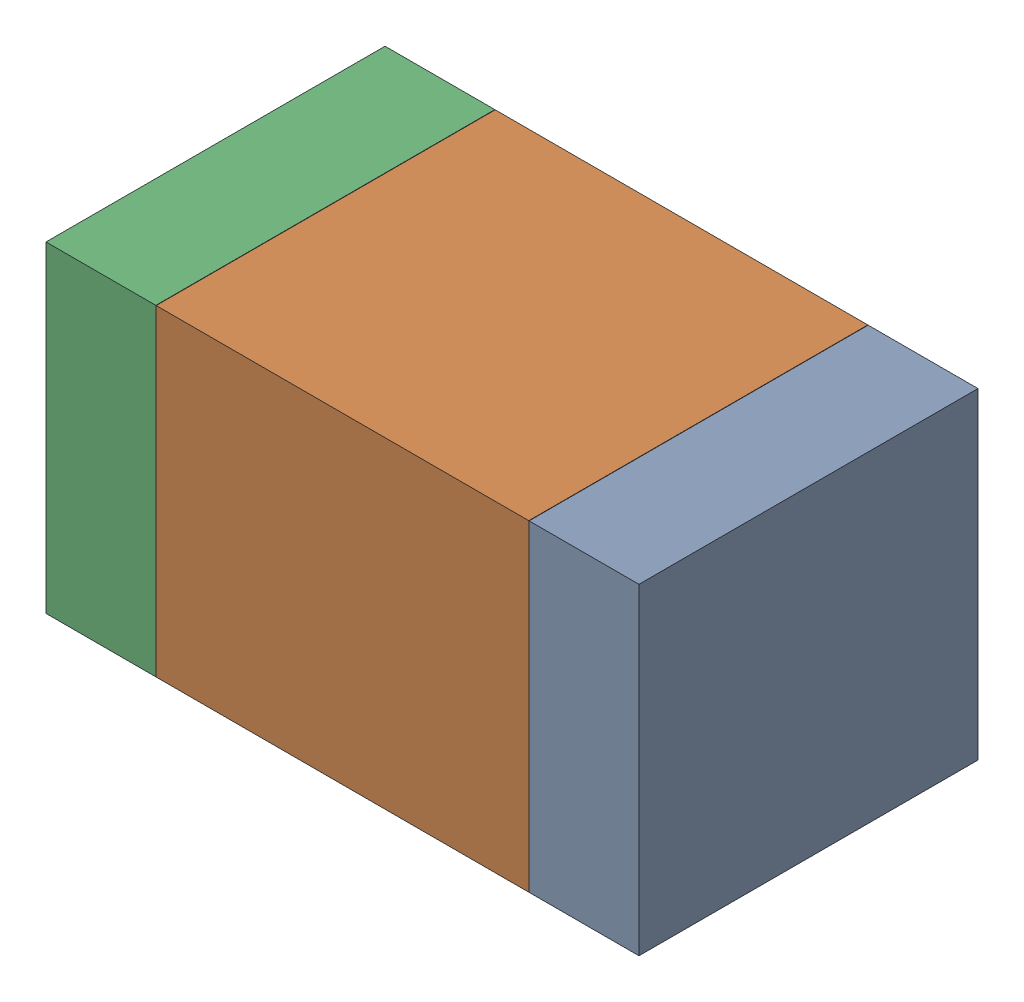
SolidWorks assembly C27, configuration Default. Lengths in mm.
Overall size (1.75 0.95 1).
6 component instances, 2 part files, 0 mates.
Components (placement in the parent):
- 6575498272-1: 6575498272 [Default] at (40.5905 5.207 0) size (0.32 0.95 1)
  - Extruded_8-1: Extruded_8 [Default] at origin size (0.32 0.95 1)
- 6575498112-1: 6575498112 [Default] at (39.878 5.207 0) size (1.1 0.95 1)
  - Extruded_9-1: Extruded_9 [Default] at origin size (1.1 0.95 1)
- 6575498272-2: 6575498272 [Default] at (39.1655 5.207 0) size (0.32 0.95 1)
  - Extruded_8-1: Extruded_8 [Default] at origin size (0.32 0.95 1)
